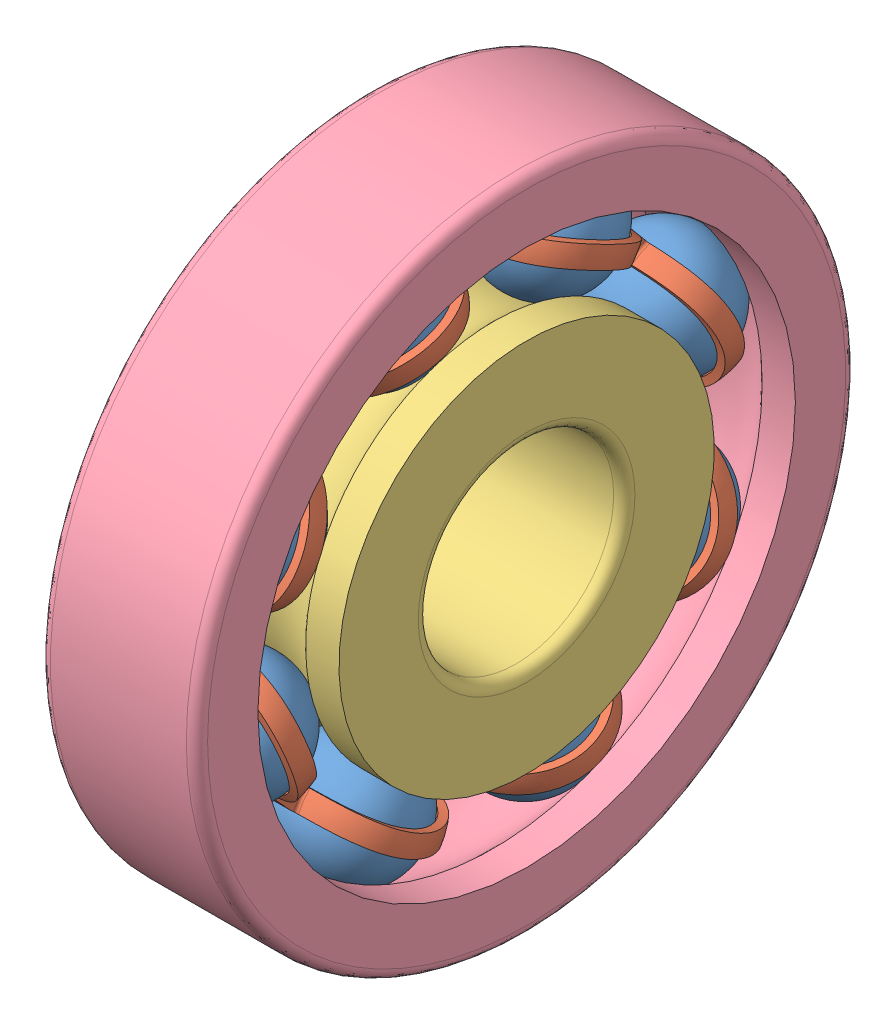
SolidWorks assembly Assembly, configuration Default. Lengths in mm.
Overall size (31 130 130).
11 component instances, 4 part files, 7 mates.
Components (placement in the parent):
- Ball-1: Ball [Default] at (92.9536 39.8475 -48.8648) x (1 0 0) z (0 0.904161 -0.427193) size (24 24 24)
- Cage-1: Cage [Default] at (100.9536 59.0711 -8.1775) x (0 0.427193 0.904161) z (-1 0 0) size (94 94 27.5)
- Inner ring-1: Inner ring [Default] at (92.9536 59.0711 -8.1775) x (1 0 0) z (0 0.904161 -0.427193) size (31 74 74)
- outer Ring-1: outer Ring [Default] at (92.9536 59.0711 -8.1775) size (31 130 130)
- Ball-2: Ball [Default] at (92.9536 16.7077 -23.3546) x (1 0 0) z (0 0.337267 -0.941409) size (24 24 24)
- Ball-3: Ball [Default] at (92.9536 18.3839 11.0461) x (1 0 0) z (0 -0.427193 -0.904161) size (24 24 24)
- Ball-4: Ball [Default] at (92.9536 43.8941 34.1859) x (1 0 0) z (0 -0.941409 -0.337267) size (24 24 24)
- Ball-5: Ball [Default] at (92.9536 78.2948 32.5097) x (1 0 0) z (0 -0.904161 0.427193) size (24 24 24)
- Ball-6: Ball [Default] at (92.9536 101.4345 6.9995) x (1 0 0) z (0 -0.337267 0.941409) size (24 24 24)
- Ball-7: Ball [Default] at (92.9536 99.7584 -27.4012) x (1 0 0) z (0 0.427193 0.904161) size (24 24 24)
- Ball-8: Ball [Default] at (92.9536 74.2482 -50.5409) x (1 0 0) z (0 0.941409 0.337267) size (24 24 24)
Mates (geometry in assembly coordinates):
- Concentric1: concentric aligned: cylinder of Inner ring-1 through (77.4536 59.0711 -8.1775) axis (-1 0 0) radius 19.2573; cylinder of outer Ring-1 through (77.4536 59.0711 -8.1775) axis (-1 0 0) radius 65
- Width1: width anti-aligned: plane of outer Ring-1 through (108.4536 112.0711 -8.1775) normal (1 0 0); plane of outer Ring-1 through (77.4536 112.0711 -8.1775) normal (-1 0 0); plane of Inner ring-1 through (77.4536 49.9475 -27.488) normal (-1 0 0); plane of Inner ring-1 through (108.4536 49.9475 -27.488) normal (1 0 0)
- Coincident1: coincident aligned: plane of Ball-1 through (92.9536 39.8475 -48.8648) normal (0 0.904161 -0.427193); plane of Inner ring-1 through (92.9536 59.0711 -8.1775) normal (0 0.904161 -0.427193)
- Coincident2: coincident aligned: plane of Ball-1; plane of Inner ring-1
- Tangent1: tangent: sphere of Ball-1; torus of Inner ring-1
- Coincident3: coincident anti-aligned: axis of Cage-1 through (91.4536 59.0711 -8.1775) axis (1 0 0); axis of Inner ring-1 through (114.1875 59.0711 -8.1775) axis (-1 0 0)
- Concentric2: concentric: sphere of Cage-1; sphere of Ball-5
